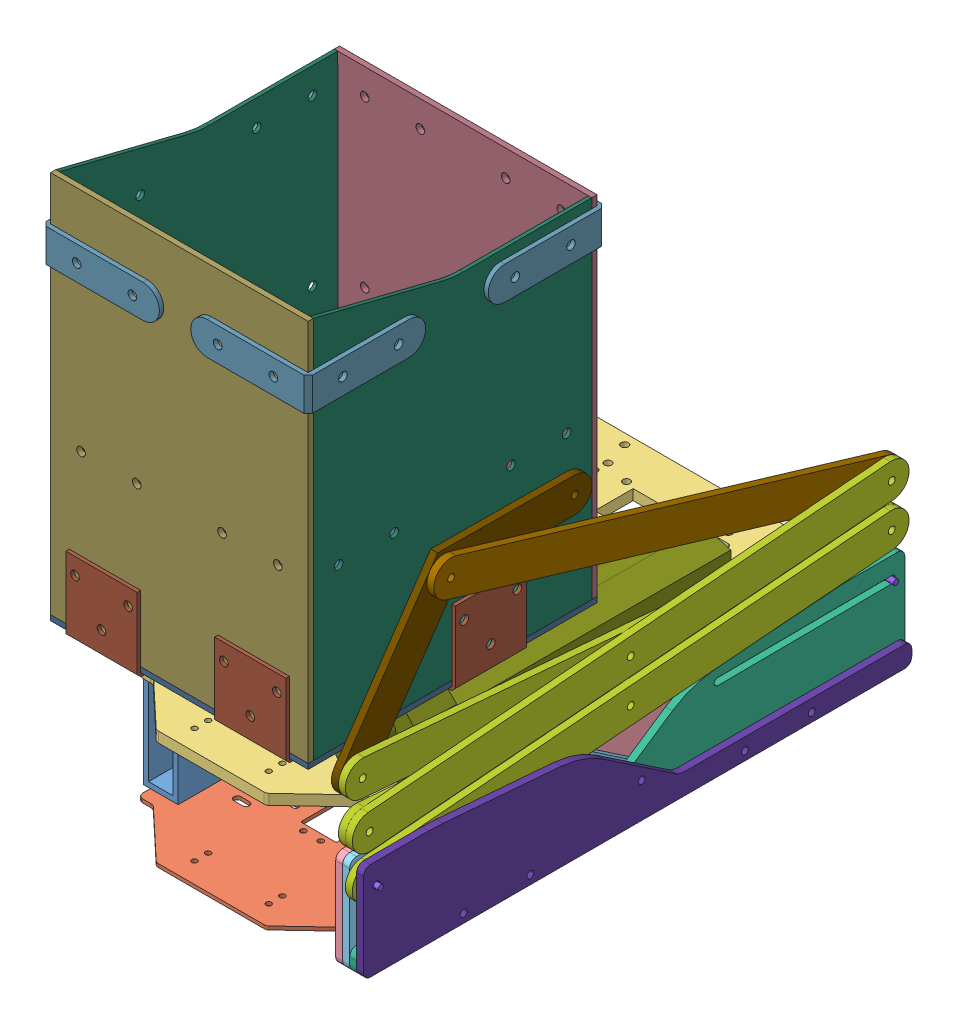
SolidWorks assembly 完整机构, configuration Default. Lengths in mm.
Overall size (169 333.21 338.26).
34 component instances, 18 part files, 56 mates.
Components (placement in the parent):
- 钢扁管（x2）-1: 钢扁管（x2） [默认] at (133.0876 164.6575 23.7796) size (20 60 240)
- 小车底板-1: 小车底板 [默认] at (-1324.7687 128.4454 -4018.955) x (0 0 1) z (-1 0 0) size (282.3 2 140.02)
- 钢扁管（x2）-2: 钢扁管（x2） [默认] at (261.1093 164.6575 23.7796) size (20 60 240)
- 小车底板(3d打印二层）-1: 小车底板(3d打印二层） [默认] at (-1324.7687 190.4454 -4018.955) x (0 0 1) z (-1 0 0) size (282.3 8 140.02)
- 滑槽板（内侧）-1: 滑槽板（内侧） [默认] at (244.4924 161.4454 143.7796) x (0 0 1) z (1 0 0) size (315 56 4)
- 滑槽板（中间）-1: 滑槽板（中间） [默认] at (252.4924 138.3918 171.4366) x (0 0 1) z (-1 0 0) size (315 56 4)
- 滑槽板（外侧）-1: 滑槽板（外侧） [默认] at (252.4924 161.4454 143.7796) x (0 0 1) z (1 0 0) size (315 56 4)
- 连杆-1: 连杆 [默认] at (252.4924 189.7257 143.7815) x (0 0.081597 -0.996665) z (1 0 0) size (321 20 4)
- 连杆-2: 连杆 [默认] at (248.4924 189.7257 143.7815) x (0 0.08193 0.996638) z (1 0 0) size (321 20 4)
- 塞打螺栓-1: 塞打螺栓 [默认] at (244.4924 177.3953 -6.2126) x (0 0.725002 0.688747) z (1 0 0) size (7 7 14.5)
- 连杆-5: 连杆 [默认] at (256.4924 214.3364 143.7774) x (0 -0.081597 0.996665) z (-1 0 0) size (321 20 4)
- 连杆-6: 连杆 [默认] at (252.4924 214.3364 143.7774) x (0 -0.08193 -0.996638) z (-1 0 0) size (321 20 4)
- 倾倒杆2-1: 倾倒杆2 [默认] at (248.4924 260.9163 108.7729) x (0 0.285829 0.958281) z (1 0 0) size (280 20 4)
- 垃圾桶2.0-1: 垃圾桶2.0 [默认] at (151.8543 243.9407 414.082) x (-1 0 0) z (0 0.000091 -1) size (153 225 171)
  - 底板-1: 底板 [默认] at (-18.6381 -5.3064 180) size (148 3 166)
  - 角铁2-1: 角铁2 [默认] at (24.1119 -7.3064 117.5) size (41 43 43)
  - 角铁2-2: 角铁2 [默认] at (-61.3881 -7.3064 117.5) size (41 43 43)
  - 角铁2-3: 角铁2 [默认] at (-61.3881 -7.3064 242.5) x (-1 0 0) z (0 0 -1) size (41 43 43)
  - 角铁2-4: 角铁2 [默认] at (24.1119 -7.3064 242.5) x (-1 0 0) z (0 0 -1) size (41 43 43)
  - 侧面板-1: 侧面板 [默认] at (-18.6381 107.6936 97) size (148 220 3)
  - 侧面板2-1: 侧面板2 [默认] at (-18.6381 97.6936 260) size (148 200 3)
  - 角铁1-1: 角铁1 [默认] at (-60.1381 182.6936 94.5) x (1 0 0) z (0 -1 0) size (67.5 67.5 19)
  - 角铁1-2: 角铁1 [默认] at (57.8619 182.6936 129.5) x (0 0 1) z (0 -1 0) size (67.5 67.5 19)
  - 角铁1-3: 角铁1 [默认] at (-95.1381 182.6936 230.5) x (0 0 -1) z (0 -1 0) size (67.5 67.5 19)
  - 角铁1-4: 角铁1 [默认] at (22.8619 182.6936 265.5) x (-1 0 0) z (0 -1 0) size (67.5 67.5 19)
- 角铁2-1: 角铁2 [默认] at (223.9924 236.6525 214.0813) x (0 -0.000091 1) z (-1 0 0) size (41 43 43)
- 角铁2-2: 角铁2 [默认] at (116.9924 236.6525 214.0813) x (0 0.000091 -1) z (1 0 0) size (41 43 43)
- 侧板2-1: 侧板2 [默认] at (242.4924 341.6507 234.0909) x (1 0 0) z (0 -0.000091 1) size (2 220 160)
- 侧板2-2: 侧板2 [默认] at (96.4924 341.6507 234.0909) x (1 0 0) z (0 -0.000091 1) size (2 220 160)
- 推杆装配体-1: 推杆装配体 [默认] at (244.4924 236.4454 255.7384) x (0 -1 0) z (1 0 0) size (40 198.5 75)
  - 底座-1: 底座 [默认] at origin size (40 198.5 75)
- 滑槽板（最外）-1: 滑槽板（最外） [默认] at (260.4924 138.3918 171.4366) x (0 0 1) z (-1 0 0) size (315 56 4)
- 塞打螺栓-2: 塞打螺栓 [默认] at (248.4924 177.4454 293.7796) x (0 -0.997785 0.066524) z (1 0 0) size (7 7 14.5)
- 倾倒杆-1: 倾倒杆 [默认] at (248.4924 243.6642 291.4563) x (0 -0.825173 0.56488) z (-1 0 0) size (153.76 80.91 4)
Mates (geometry in assembly coordinates):
- 同心1: concentric anti-aligned: cylinder of 钢扁管（x2）-1 through (106.4708 130.4454 213.7796) axis (0 1 0) radius 2; cylinder of 小车底板-1 through (106.4708 130.4454 213.7796) axis (0 -1 0) radius 2
- 同心2: concentric anti-aligned: cylinder of 钢扁管（x2）-1 through (106.4708 130.4454 73.7796) axis (0 1 0) radius 2; cylinder of 小车底板-1 through (106.4708 130.4454 73.7796) axis (0 -1 0) radius 2
- 重合1: coincident anti-aligned: plane of 钢扁管（x2）-1 through (96.4708 130.4454 263.7796) normal (0 -1 0); plane of 小车底板-1 through (103.4708 130.4454 19.4797) normal (0 1 0)
- 重合2: coincident anti-aligned: plane of 小车底板-1 through (103.4708 130.4454 19.4797) normal (0 1 0); plane of 钢扁管（x2）-2 through (224.4924 130.4454 263.7796) normal (0 -1 0)
- 同心3: concentric anti-aligned: cylinder of 小车底板-1 through (234.4924 130.4454 213.7796) axis (0 -1 0) radius 2; cylinder of 钢扁管（x2）-2 through (234.4924 130.4454 213.7796) axis (0 1 0) radius 2
- 同心4: concentric anti-aligned: cylinder of 小车底板-1 through (234.4924 130.4454 73.7796) axis (0 -1 0) radius 2; cylinder of 钢扁管（x2）-2 through (234.4924 130.4454 73.7796) axis (0 1 0) radius 2
- 同心5: concentric anti-aligned: cylinder of 钢扁管（x2）-1 through (106.4708 130.4454 128.7796) axis (0 1 0) radius 2; cylinder of 小车底板(3d打印二层）-1 through (106.4708 196.4454 128.7796) axis (0 -1 0) radius 2
- 同心6: concentric anti-aligned: cylinder of 钢扁管（x2）-2 through (234.4924 130.4454 243.7796) axis (0 1 0) radius 3.05; cylinder of 小车底板(3d打印二层）-1 through (234.4924 196.4454 243.7796) axis (0 -1 0) radius 2
- 重合4: coincident anti-aligned: plane of 钢扁管（x2）-2 through (224.4924 190.4454 263.7796) normal (0 1 0); plane of 小车底板(3d打印二层）-1 through (103.4708 190.4454 19.4797) normal (0 -1 0)
- 重合5: coincident anti-aligned: plane of 钢扁管（x2）-2 through (244.4924 190.4454 263.7796) normal (1 0 0); plane of 滑槽板（内侧）-1 through (244.4924 185.4454 297.2796) normal (-1 0 0)
- 同心11: concentric anti-aligned: cylinder of 钢扁管（x2）-2 through (4.4924 138.4454 43.7796) axis (1 0 0) radius 2; cylinder of 滑槽板（内侧）-1 through (248.4924 138.4454 43.7796) axis (-1 0 0) radius 2
- 同心12: concentric anti-aligned: cylinder of 钢扁管（x2）-2 through (4.4924 184.4454 43.7796) axis (1 0 0) radius 2; cylinder of 滑槽板（内侧）-1 through (248.4924 184.4454 43.7796) axis (-1 0 0) radius 2
- 同心13: concentric aligned: cylinder of 钢扁管（x2）-2 through (4.4924 138.4454 43.7796) axis (1 0 0) radius 2; cylinder of 滑槽板（中间）-1 through (248.4924 138.4454 43.7796) axis (1 0 0) radius 2
- 同心14: concentric anti-aligned: cylinder of 滑槽板（内侧）-1 through (248.4924 138.4454 82.1096) axis (-1 0 0) radius 2; cylinder of 滑槽板（中间）-1 through (248.4924 138.4454 82.1096) axis (1 0 0) radius 2
- 重合8: coincident anti-aligned: plane of 滑槽板（内侧）-1 through (248.4924 185.4454 297.2796) normal (1 0 0); plane of 滑槽板（中间）-1 through (248.4924 138.3918 171.4366) normal (-1 0 0)
- 同心18: concentric anti-aligned: cylinder of 钢扁管（x2）-2 through (4.4924 138.4454 243.7796) axis (1 0 0) radius 2; cylinder of 滑槽板（外侧）-1 through (256.4924 138.4454 243.7796) axis (-1 0 0) radius 2
- 同心19: concentric anti-aligned: cylinder of 钢扁管（x2）-2 through (4.4924 138.4454 205.4496) axis (1 0 0) radius 2; cylinder of 滑槽板（外侧）-1 through (256.4924 138.4454 205.4496) axis (-1 0 0) radius 2
- 重合9: coincident anti-aligned: plane of 滑槽板（中间）-1 through (252.4924 138.3918 171.4366) normal (1 0 0); plane of 滑槽板（外侧）-1 through (252.4924 185.4454 297.2796) normal (-1 0 0)
- 相切1: tangent anti-aligned: plane of 滑槽板（内侧）-1 through (248.4924 173.8954 -6.2464) normal (0 0.999973 0.007314); cylinder of 塞打螺栓-1 through (247.9924 177.3953 -6.2126) axis (-1 0 0) radius 3.5
- 同心26: concentric anti-aligned: cylinder of 滑槽板（中间）-1 through (248.4924 177.4454 293.7796) axis (1 0 0) radius 3.55; cylinder of 连杆-1 through (256.4924 177.4454 293.7796) axis (-1 0 0) radius 2
- 同心27: concentric aligned: cylinder of 连杆-2 through (252.4924 177.3953 -6.2126) axis (-1 0 0) radius 2; cylinder of 塞打螺栓-1 through (252.9924 177.3953 -6.2126) axis (-1 0 0) radius 2
- 重合15: coincident anti-aligned: plane of 滑槽板（外侧）-1 through (252.4924 185.4454 297.2796) normal (-1 0 0); plane of 连杆-2 through (252.4924 189.7257 143.7815) normal (1 0 0)
- 同心28: concentric aligned: cylinder of 连杆-1 through (256.4924 189.7257 143.7815) axis (-1 0 0) radius 2; cylinder of 连杆-2 through (252.4924 189.7257 143.7815) axis (-1 0 0) radius 2
- 重合17: coincident anti-aligned: plane of 滑槽板（中间）-1 through (252.4924 138.3918 171.4366) normal (1 0 0); plane of 连杆-1 through (252.4924 189.7257 143.7815) normal (-1 0 0)
- 重合20: coincident aligned: plane of 滑槽板（内侧）-1 through (244.4924 185.4454 297.2796) normal (-1 0 0); plane of 塞打螺栓-1 through (244.4924 177.3953 -6.2126) normal (-1 0 0)
- 同心39: concentric anti-aligned: cylinder of 连杆-2 through (252.4924 202.0561 293.7755) axis (-1 0 0) radius 2; cylinder of 连杆-5 through (252.4924 202.0561 293.7755) axis (1 0 0) radius 2
- 重合25: coincident anti-aligned: plane of 连杆-2 through (252.4924 189.7257 143.7815) normal (1 0 0); plane of 连杆-5 through (252.4924 214.3364 143.7774) normal (-1 0 0)
- 同心40: concentric anti-aligned: cylinder of 连杆-1 through (256.4924 202.006 -6.2167) axis (-1 0 0) radius 2; cylinder of 连杆-6 through (248.4924 202.006 -6.2167) axis (1 0 0) radius 2
- 同心41: concentric aligned: cylinder of 连杆-5 through (252.4924 214.3364 143.7774) axis (1 0 0) radius 2; cylinder of 连杆-6 through (248.4924 214.3364 143.7774) axis (1 0 0) radius 2
- 重合26: coincident anti-aligned: plane of 连杆-1 through (252.4924 189.7257 143.7815) normal (-1 0 0); plane of 连杆-6 through (252.4924 214.3364 143.7774) normal (1 0 0)
- 重合28: coincident anti-aligned: plane of 连杆-5 through (252.4924 214.3364 143.7774) normal (-1 0 0); plane of 倾倒杆2-1 through (252.4924 226.6168 -6.2208) normal (1 0 0)
- 同心45: concentric anti-aligned: cylinder of 连杆-5 through (252.4924 226.6168 -6.2208) axis (1 0 0) radius 2; cylinder of 倾倒杆2-1 through (252.4924 226.6168 -6.2208) axis (-1 0 0) radius 2
- 重合30: coincident anti-aligned: plane of 垃圾桶2.0-1/底板-1 through (170.4924 238.6507 234.0815) normal (0 -1 -0.000091); plane of 角铁2-2 through (116.9924 238.6525 214.0815) normal (0 1 0.000091)
- 重合31: coincident aligned: cylinder of 垃圾桶2.0-1/底板-1 through (127.9924 238.6512 229.3315) axis (0 1 0.000091) radius 2.5; circle of 角铁2-2
- 同心52: concentric anti-aligned: cylinder of 垃圾桶2.0-1/底板-1 through (108.4924 238.6525 214.0815) axis (0 1 0.000091) radius 2.5; cylinder of 角铁2-2 through (108.4924 238.6525 214.0815) axis (0 -1 -0.000091) radius 2.5
- 重合32: coincident anti-aligned: plane of 垃圾桶2.0-1/底板-1 through (170.4924 238.6507 234.0815) normal (0 -1 -0.000091); plane of 角铁2-1 through (223.9924 238.6525 214.0815) normal (0 1 0.000091)
- 同心53: concentric anti-aligned: cylinder of 垃圾桶2.0-1/底板-1 through (212.9924 238.6512 229.3315) axis (0 1 0.000091) radius 2.5; cylinder of 角铁2-1 through (212.9924 238.6512 229.3315) axis (0 -1 -0.000091) radius 2.5
- 同心54: concentric anti-aligned: cylinder of 垃圾桶2.0-1/底板-1 through (232.4924 238.6525 214.0815) axis (0 1 0.000091) radius 2.5; cylinder of 角铁2-1 through (232.4924 238.6525 214.0815) axis (0 -1 -0.000091) radius 2.5
- 同心55: concentric aligned: cylinder of 角铁2-1 through (246.4924 270.1512 229.3344) axis (-1 0 0) radius 2.5; cylinder of 侧板2-1 through (244.4924 270.1512 229.3344) axis (-1 0 0) radius 2.5
- 重合33: coincident anti-aligned: cylinder of 角铁2-1 through (246.4924 270.1539 198.8344) axis (-1 0 0) radius 2.5; circle of 侧板2-1
- 重合34: coincident anti-aligned: plane of 角铁2-1 through (244.4924 238.6507 234.5815) normal (-1 0 0); plane of 侧板2-1 through (244.4924 491.6513 227.9493) normal (1 0 0)
- 同心56: concentric anti-aligned: cylinder of 角铁2-2 through (94.4924 250.6525 214.0826) axis (1 0 0) radius 2.5; cylinder of 侧板2-2 through (98.4924 250.6525 214.0826) axis (-1 0 0) radius 2.5
- 同心57: concentric anti-aligned: cylinder of 角铁2-2 through (94.4924 270.1512 229.3344) axis (1 0 0) radius 2.5; cylinder of 侧板2-2 through (98.4924 270.1512 229.3344) axis (-1 0 0) radius 2.5
- 重合36: coincident anti-aligned: plane of 角铁2-2 through (96.4924 238.6544 193.5815) normal (1 0 0); plane of 侧板2-2 through (96.4924 491.6513 227.9493) normal (-1 0 0)
- 同心65: concentric anti-aligned: cylinder of 滑槽板（外侧）-1 through (256.4924 138.4454 243.7796) axis (-1 0 0) radius 2; cylinder of 滑槽板（最外）-1 through (256.4924 138.4454 243.7796) axis (1 0 0) radius 2
- 重合57: coincident anti-aligned: plane of 滑槽板（外侧）-1 through (256.4924 185.4454 297.2796) normal (1 0 0); plane of 滑槽板（最外）-1 through (256.4924 138.3918 171.4366) normal (-1 0 0)
- 同心66: concentric anti-aligned: cylinder of 滑槽板（外侧）-1 through (256.4924 138.4454 43.7796) axis (-1 0 0) radius 2; cylinder of 滑槽板（最外）-1 through (256.4924 138.4454 43.7796) axis (1 0 0) radius 2
- 同心67: concentric aligned: cylinder of 连杆-1 through (256.4924 177.4454 293.7796) axis (-1 0 0) radius 2; cylinder of 塞打螺栓-2 through (256.9924 177.4454 293.7796) axis (-1 0 0) radius 2
- 重合58: coincident anti-aligned: plane of 滑槽板（内侧）-1 through (248.4924 185.4454 297.2796) normal (1 0 0); plane of 塞打螺栓-2 through (248.4924 177.4454 293.7796) normal (-1 0 0)
- 重合61: coincident anti-aligned: plane of 小车底板(3d打印二层）-1 through (103.4708 196.4454 19.4797) normal (0 1 0); plane of 推杆装配体-1/底座-1 through (236.4924 196.4454 231.7384) normal (0 -1 0)
- 重合63: coincident anti-aligned: plane of 倾倒杆2-1 through (248.4924 226.6168 -6.2208) normal (-1 0 0); plane of 倾倒杆-1 through (248.4924 302.6411 167.9516) normal (1 0 0)
- 同心68: concentric aligned: cylinder of 连杆-6 through (248.4924 226.6668 293.7714) axis (1 0 0) radius 2; cylinder of 倾倒杆-1 through (244.4924 226.6668 293.7714) axis (1 0 0) radius 2
- 同心69: concentric anti-aligned: cylinder of 倾倒杆2-1 through (252.4924 300.9324 242.9322) axis (-1 0 0) radius 2; cylinder of 倾倒杆-1 through (244.4924 300.9324 242.9322) axis (1 0 0) radius 2
- 同心70: concentric anti-aligned: cylinder of 侧板2-1 through (244.4924 300.9324 242.9322) axis (-1 0 0) radius 2; cylinder of 倾倒杆-1 through (244.4924 300.9324 242.9322) axis (1 0 0) radius 2
- 同心71: concentric anti-aligned: cylinder of 侧板2-1 through (244.4924 302.6411 167.9516) axis (-1 0 0) radius 2; cylinder of 倾倒杆-1 through (244.4924 302.6411 167.9516) axis (1 0 0) radius 2
- 重合65: coincident anti-aligned: plane of 侧板2-1 through (244.4924 491.6513 227.9493) normal (1 0 0); plane of 倾倒杆-1 through (244.4924 302.6411 167.9516) normal (-1 0 0)
